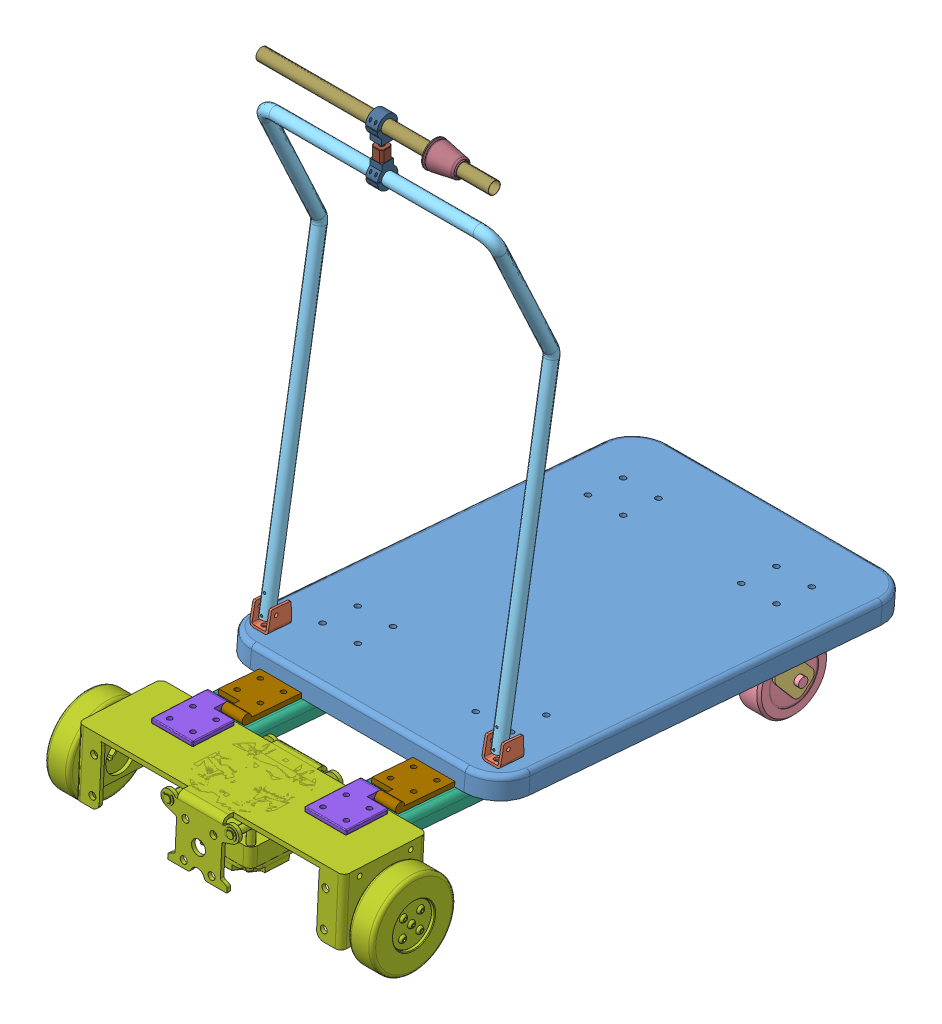
SolidWorks assembly PlanB, configuration 默认. Lengths in mm.
Overall size (705 1408.46 1250.68).
22 component instances, 13 part files, 43 mates.
Components (placement in the parent):
- panel^PlanB-1: panel^PlanB [默认] at (0 -46.2536 2.7021) x (1 0 0) z (0 0.081432 0.996679) size (600 45 900) (virtual)
- Hinge^PlanB-1: Hinge^PlanB [默认] at (-250 37.3717 412.2155) x (1 0 0) z (0 0.081432 0.996679) size (40 45 50) (virtual)
- Hinge^PlanB-2: Hinge^PlanB [默认] at (250 37.3717 412.2155) x (1 0 0) z (0 0.081432 0.996679) size (40 45 50) (virtual)
- Wheelasssembly-4: Wheelasssembly [Default] at (202.9636 -55.6778 -399.5053) x (-1 0 0) z (0 0.081432 0.996679) size (100 193.9 158.85)
  - 1TrolleyWheelSupport-1: 1TrolleyWheelSupport [Default] at (37.9636 23.3598 114.9093) size (100 152.99 117.95)
  - 1TrolleyWheel-1: 1TrolleyWheel [Default] at (37.9636 142.258 89.0548) size (90 150 150)
- Wheelasssembly-5: Wheelasssembly [Default] at (-127.0364 -55.6778 -399.5053) x (-1 0 0) z (0 0.081432 0.996679) size (100 193.9 158.85)
  - 1TrolleyWheelSupport-1: 1TrolleyWheelSupport [Default] at (37.9636 23.3598 114.9093) size (100 152.99 117.95)
  - 1TrolleyWheel-1: 1TrolleyWheel [Default] at (37.9636 142.258 89.0548) size (90 150 150)
- 零件2^PlanB-1: 零件2^PlanB [默认] at (2 1012.3447 410.1357) x (1 0 0) z (0 0.162494 0.98671) size (526 960.26 195.17) (virtual)
- A^PlanB-1: A^PlanB [默认] at (-165 -30.4734 232.6826) x (1 0 0) z (0 0.081432 0.996679) size (126 33 500) (virtual)
- A^PlanB-2: A^PlanB [默认] at (165 -30.4734 232.6826) x (1 0 0) z (0 0.081432 0.996679) size (126 33 500) (virtual)
- 平衡车-1: 平衡车 [默认] at (0 15.3984 676.0987) x (1 0 0) z (0 0.050067 0.998746) size (705 187.5 231.75)
- 零件3^PlanB-2: 零件3^PlanB [默认] at (-165 23.5726 639.4263) x (-1 0 0) z (0 0.050067 0.998746) size (90 20 126.61) (virtual)
- 零件3^PlanB-3: 零件3^PlanB [默认] at (165 23.5726 639.4263) x (-1 0 0) z (0 0.050067 0.998746) size (90 20 126.61) (virtual)
- 零件7^PlanB-1: 零件7^PlanB [默认] at (165 3.9485 494.3418) x (1 0 0) z (0 -0.081432 -0.996679) size (90 20 129.31) (virtual)
- 零件7^PlanB-2: 零件7^PlanB [默认] at (-165 3.9485 494.3418) x (1 0 0) z (0 -0.081432 -0.996679) size (90 20 129.31) (virtual)
- 零件6^PlanB-1: 零件6^PlanB [默认] at (12.4154 1012.3447 410.1357) x (1 0 0) z (0 -0.006138 0.999981) size (25 53 43.95) (virtual)
- 零件8^PlanB-1: 零件8^PlanB [默认] at (12.4154 1043.3441 410.326) x (1 0 0) z (0 -0.006138 0.999981) size (25 35 25) (virtual)
- 零件9^PlanB-1: 零件9^PlanB [默认] at (4.9998 1109.3429 410.7311) x (-1 0 0) z (0 0.620808 -0.783963) size (500 26 26) (virtual)
- 零件6^PlanB-2: 零件6^PlanB [默认] at (12.4154 1109.3429 410.7311) x (-1 0 0) z (0 -0.006138 0.999981) size (25 53 43.95) (virtual)
- 零件1^PlanB-1: 零件1^PlanB [默认] at (126.6106 1109.3429 410.7311) size (60 56.09 56.09) (virtual)
Mates (geometry in assembly coordinates):
- 重合1: coincident anti-aligned: plane of panel^不延伸的-1 through (230 29.5412 377.7756) normal (0 0.996679 -0.081432); plane of Hinge^不延伸的-1 through (-235 32.3883 412.6226) normal (0 -0.996679 0.081432)
- 同心1: concentric aligned: cylinder of panel^不延伸的-1 through (-250 31.3704 400.1641) axis (0 0.996679 -0.081432) radius 6; cylinder of Hinge^不延伸的-1 through (-250 36.3538 399.757) axis (0 0.996679 -0.081432) radius 6
- 同心2: concentric aligned: cylinder of panel^不延伸的-1 through (-250 29.3346 375.2472) axis (0 0.996679 -0.081432) radius 6; cylinder of Hinge^不延伸的-1 through (-250 34.318 374.84) axis (0 0.996679 -0.081432) radius 6
- 重合2: coincident anti-aligned: plane of panel^不延伸的-1 through (230 29.5412 377.7756) normal (0 0.996679 -0.081432); plane of Hinge^不延伸的-2 through (265 32.3883 412.6226) normal (0 -0.996679 0.081432)
- 同心3: concentric aligned: cylinder of panel^不延伸的-1 through (250 31.3704 400.1641) axis (0 0.996679 -0.081432) radius 6; cylinder of Hinge^不延伸的-2 through (250 36.3538 399.757) axis (0 0.996679 -0.081432) radius 6
- 同心4: concentric aligned: cylinder of panel^不延伸的-1 through (250 29.3346 375.2472) axis (0 0.996679 -0.081432) radius 6; cylinder of Hinge^不延伸的-2 through (250 34.318 374.84) axis (0 0.996679 -0.081432) radius 6
- 重合9: coincident anti-aligned: plane of panel^不延伸的-1 through (230 -15.3093 381.4401) normal (0 -0.996679 0.081432); plane of Wheelasssembly-4/1TrolleyWheelSupport-1 through (165 -69.6027 -283.0754) normal (0 0.996679 -0.081432)
- 同心18: concentric anti-aligned: cylinder of panel^不延伸的-1 through (127 -27.8358 -324.4824) axis (0 0.996679 -0.081432) radius 6; cylinder of Wheelasssembly-4/1TrolleyWheelSupport-1 through (127 -72.6864 -320.8179) axis (0 -0.996679 0.081432) radius 5.5
- 同心19: concentric anti-aligned: cylinder of panel^不延伸的-1 through (203 -27.8358 -324.4824) axis (0 0.996679 -0.081432) radius 6; cylinder of Wheelasssembly-4/1TrolleyWheelSupport-1 through (203 -72.6864 -320.8179) axis (0 -0.996679 0.081432) radius 5.5
- 重合10: coincident anti-aligned: plane of panel^不延伸的-1 through (230 -15.3093 381.4401) normal (0 -0.996679 0.081432); plane of Wheelasssembly-5/1TrolleyWheelSupport-1 through (-165 -69.6027 -283.0754) normal (0 0.996679 -0.081432)
- 同心20: concentric anti-aligned: cylinder of panel^不延伸的-1 through (-203 -27.8358 -324.4824) axis (0 0.996679 -0.081432) radius 6; cylinder of Wheelasssembly-5/1TrolleyWheelSupport-1 through (-203 -72.6864 -320.8179) axis (0 -0.996679 0.081432) radius 5.5
- 同心21: concentric anti-aligned: cylinder of panel^不延伸的-1 through (-127 -27.8358 -324.4824) axis (0 0.996679 -0.081432) radius 6; cylinder of Wheelasssembly-5/1TrolleyWheelSupport-1 through (-127 -72.6864 -320.8179) axis (0 -0.996679 0.081432) radius 5.5
- 重合28: coincident anti-aligned: plane of panel^不延伸的-1 through (230 -15.3093 381.4401) normal (0 -0.996679 0.081432); plane of A^不延伸的-1 through (-215 13.2328 730.7777) normal (0 0.996679 -0.081432)
- 同心51: concentric aligned: cylinder of panel^不延伸的-1 through (-203 25.0297 322.5576) axis (0 0.996679 -0.081432) radius 6; cylinder of A^不延伸的-1 through (-203 -19.8208 326.2221) axis (0 0.996679 -0.081432) radius 5.25
- 同心52: concentric aligned: cylinder of panel^不延伸的-1 through (-127 18.8408 246.81) axis (0 0.996679 -0.081432) radius 6; cylinder of A^不延伸的-1 through (-127 -26.0097 250.4745) axis (0 0.996679 -0.081432) radius 5.25
- 重合29: coincident anti-aligned: plane of panel^不延伸的-1 through (230 -15.3093 381.4401) normal (0 -0.996679 0.081432); plane of A^不延伸的-2 through (115 13.2328 730.7777) normal (0 0.996679 -0.081432)
- 同心53: concentric aligned: cylinder of panel^不延伸的-1 through (127 25.0297 322.5576) axis (0 0.996679 -0.081432) radius 6; cylinder of A^不延伸的-2 through (127 -19.8208 326.2221) axis (0 0.996679 -0.081432) radius 5.25
- 同心54: concentric aligned: cylinder of panel^不延伸的-1 through (203 18.8408 246.81) axis (0 0.996679 -0.081432) radius 6; cylinder of A^不延伸的-2 through (203 -26.0097 250.4745) axis (0 0.996679 -0.081432) radius 5.25
- 重合32: coincident anti-aligned: plane of 平衡车-1 through (274.5 11.4933 598.1966) normal (0 0.998746 -0.050067); plane of 零件3^不延伸的-3 through (165 13.5852 639.927) normal (0 -0.998746 0.050067)
- 同心57: concentric anti-aligned: cylinder of 平衡车-1 through (190 14.8368 664.8956) axis (0 0.998746 -0.050067) radius 5.25; cylinder of 零件3^不延伸的-3 through (190 14.8368 664.8956) axis (0 -0.998746 0.050067) radius 5.25
- 同心58: concentric anti-aligned: cylinder of 平衡车-1 through (140 12.3335 614.9583) axis (0 0.998746 -0.050067) radius 5.25; cylinder of 零件3^不延伸的-3 through (140 12.3335 614.9583) axis (0 -0.998746 0.050067) radius 5.25
- 重合33: coincident anti-aligned: plane of 平衡车-1 through (274.5 11.4933 598.1966) normal (0 0.998746 -0.050067); plane of 零件3^不延伸的-2 through (-165 13.5852 639.927) normal (0 -0.998746 0.050067)
- 同心59: concentric anti-aligned: cylinder of 平衡车-1 through (-140 12.3335 614.9583) axis (0 0.998746 -0.050067) radius 5.25; cylinder of 零件3^不延伸的-2 through (-140 12.3335 614.9583) axis (0 -0.998746 0.050067) radius 5.25
- 同心60: concentric anti-aligned: cylinder of 平衡车-1 through (-190 14.8368 664.8956) axis (0 0.998746 -0.050067) radius 5.25; cylinder of 零件3^不延伸的-2 through (-190 14.8368 664.8956) axis (0 -0.998746 0.050067) radius 5.25
- 重合34: coincident anti-aligned: plane of 零件3^不延伸的-3 through (165 23.5726 639.4263) normal (1 0 0); plane of 零件7^不延伸的-1 through (165 3.9485 494.3418) normal (-1 0 0)
- 同心61: concentric anti-aligned: cylinder of 零件3^不延伸的-3 through (78.2847 10 568.4085) axis (1 0 0) radius 10; cylinder of 零件7^不延伸的-1 through (254.1084 10 568.4085) axis (-1 0 0) radius 10
- 重合35: coincident anti-aligned: plane of 零件3^不延伸的-2 through (-165 23.5726 639.4263) normal (1 0 0); plane of 零件7^不延伸的-2 through (-165 3.9485 494.3418) normal (-1 0 0)
- 同心62: concentric anti-aligned: cylinder of 零件3^不延伸的-2 through (-251.7153 10 568.4085) axis (1 0 0) radius 10; cylinder of 零件7^不延伸的-2 through (-75.8916 10 568.4085) axis (-1 0 0) radius 10
- 重合38: coincident anti-aligned: plane of A^不延伸的-2 through (115 13.2328 730.7777) normal (0 0.996679 -0.081432); plane of 零件7^不延伸的-1 through (165 -6.0183 495.1561) normal (0 -0.996679 0.081432)
- 重合39: coincident anti-aligned: plane of A^不延伸的-1 through (-215 13.2328 730.7777) normal (0 0.996679 -0.081432); plane of 零件7^不延伸的-2 through (-165 -6.0183 495.1561) normal (0 -0.996679 0.081432)
- 同心64: concentric anti-aligned: cylinder of A^不延伸的-2 through (190 -8.0541 470.2392) axis (0 0.996679 -0.081432) radius 5.25; cylinder of 零件7^不延伸的-1 through (190 -8.0541 470.2392) axis (0 -0.996679 0.081432) radius 5.25
- 同心65: concentric anti-aligned: cylinder of A^不延伸的-1 through (-190 -3.9825 520.0731) axis (0 0.996679 -0.081432) radius 5.25; cylinder of 零件7^不延伸的-2 through (-190 -3.9825 520.0731) axis (0 -0.996679 0.081432) radius 5.25
- 同心66: concentric aligned: cylinder of Hinge^PlanB-2 through (265 62.5237 395.1105) axis (1 0 0) radius 4; cylinder of 零件2^PlanB-1 through (-261 62.5237 395.1105) axis (1 0 0) radius 5
- 相切1: tangent anti-aligned: plane of Hinge^PlanB-2 through (265 37.3717 412.2155) normal (-1 0 0); cylinder of 零件2^PlanB-1 through (252 731.2513 284.9827) axis (0 -0.98671 0.162494) radius 13
- 同心67: concentric anti-aligned: cylinder of 零件2^PlanB-1 through (2 1012.3447 410.1357) axis (1 0 0) radius 13; cylinder of 零件6^PlanB-1 through (24.9154 1012.3447 410.1357) axis (-1 0 0) radius 13
- 重合40: coincident anti-aligned: plane of 零件6^PlanB-1 through (24.9154 1043.3441 410.326) normal (0 0.999981 0.006138); plane of 零件8^PlanB-1 through (12.4154 1043.3441 410.326) normal (0 -0.999981 -0.006138)
- 重合41: coincident aligned: plane of 零件6^PlanB-1 through (24.9154 1012.3447 410.1357) normal (1 0 0); plane of 零件8^PlanB-1 through (24.9154 1068.3897 402.9796) normal (1 0 0)
- 重合42: coincident aligned: plane of 零件6^PlanB-1 through (24.9154 1012.4214 397.6359) normal (0 0.006138 -0.999981); plane of 零件8^PlanB-1 through (4.9154 1068.4204 397.9797) normal (0 0.006138 -0.999981)
- 同心68: concentric aligned: cylinder of 零件9^PlanB-1 through (-245.0002 1109.3429 410.7311) axis (1 0 0) radius 13; cylinder of 零件6^PlanB-2 through (-0.0846 1109.3429 410.7311) axis (1 0 0) radius 13
- 重合43: coincident anti-aligned: plane of 零件8^PlanB-1 through (12.4154 1078.3435 410.5408) normal (0 0.999981 0.006138); plane of 零件6^PlanB-2 through (-0.0846 1078.3435 410.5408) normal (0 -0.999981 -0.006138)
- 重合44: coincident aligned: plane of 零件8^PlanB-1 through (4.9154 1068.4204 397.9797) normal (0 0.006138 -0.999981); plane of 零件6^PlanB-2 through (-0.0846 1109.4196 398.2313) normal (0 0.006138 -0.999981)
- 重合45: coincident aligned: plane of 零件8^PlanB-1 through (24.9154 1068.3897 402.9796) normal (1 0 0); plane of 零件6^PlanB-2 through (24.9154 1109.3429 410.7311) normal (1 0 0)
- 同心69: concentric anti-aligned: cylinder of 零件9^PlanB-1 through (-245.0002 1109.3429 410.7311) axis (1 0 0) radius 13; cylinder of 零件1^PlanB-1 through (126.6106 1109.3429 410.7311) axis (-1 0 0) radius 13
